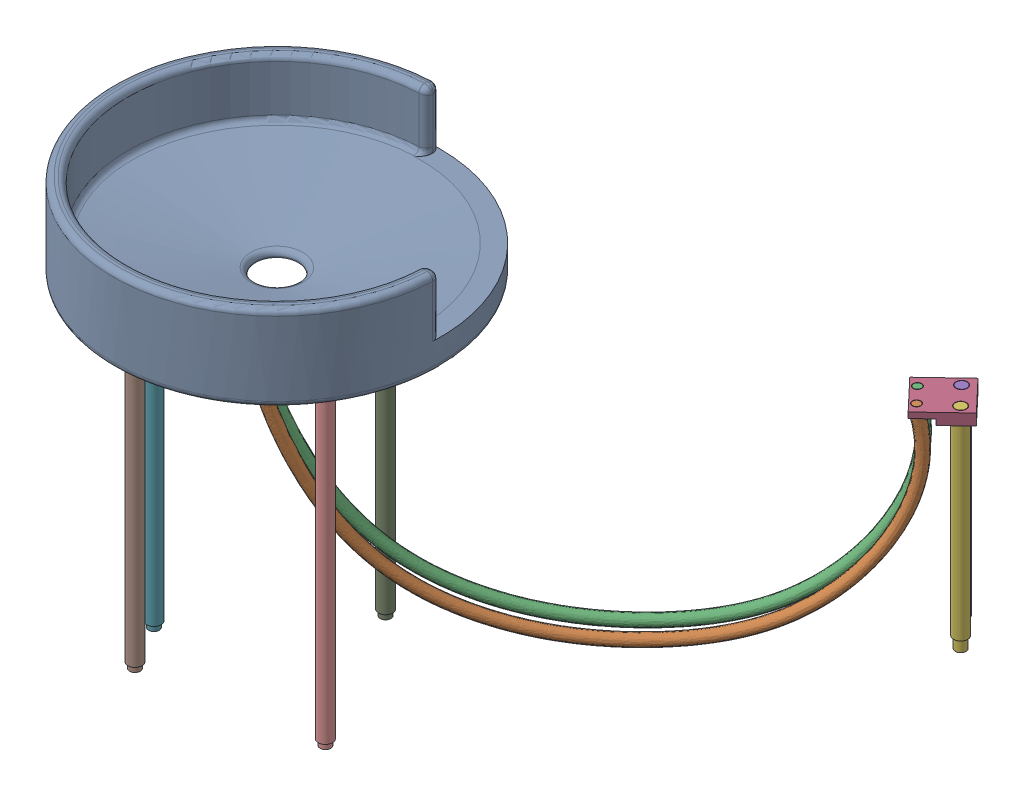
SolidWorks assembly Ensamblaje, configuration Predeterminado. Lengths in mm.
Overall size (176.61 150.24 195.69).
10 component instances, 5 part files, 20 mates.
Components (placement in the parent):
- Base-1: Base [Predeterminado] at (-10.0904 -19.4956 1.3876) size (115 30 115)
- Slide-1: Slide [Predeterminado] at (-13.6259 -19.4956 11.9942) x (0.642217 0 -0.766523) z (0 -1 0) size (175.9 4.02 118.54)
- Slide-2: Slide [Predeterminado] at (-20.697 -19.4956 4.9232) x (0.653468 0 -0.756954) z (0 -1 0) size (175.9 4.02 118.54)
- Little Base-1: Little Base [Predeterminado] at (96.6014 -65.7362 -124.4757) x (0.725915 0 -0.687784) z (-0.687784 0 -0.725915) size (17 4 15)
- Pilar Corto-1: Pilar Corto [Predeterminado] at (97.8618 -135.7362 -131.8691) x (0.841988 0 0.539497) z (-0.539497 0 0.841988) size (5 74 5)
- Pilar Corto-2: Pilar Corto [Predeterminado] at (104.0519 -135.7362 -125.3358) x (-0.528786 0 -0.848755) z (0.848755 0 -0.528786) size (5 74 5)
- Pilar Largo-1: Pilar Largo [Predeterminado] at (-44.241 -137.4956 10.5383) size (5 122 5)
- Pilar Largo-2: Pilar Largo [Predeterminado] at (-35.0904 -137.4956 26.3876) x (0.980301 0 0.197508) z (-0.197508 0 0.980301) size (5 122 5)
- Pilar Largo-3: Pilar Largo [Predeterminado] at (-7.009 -137.4956 -33.8332) size (5 122 5)
- Pilar Largo-4: Pilar Largo [Predeterminado] at (21.9524 -137.4956 16.3294) size (5 122 5)
Mates (geometry in assembly coordinates):
- Concéntrica2: concentric anti-aligned: circle of Base-1; circle of Slide-1
- Coincidente2: coincident anti-aligned: plane of Base-1 through (-13.6259 -17.4956 11.9942) normal (0 -1 0); plane of Slide-1 through (-13.6259 -17.4956 11.9942) normal (0 1 0)
- Concéntrica3: concentric anti-aligned: circle of Base-1; circle of Slide-2
- Coincidente3: coincident anti-aligned: plane of Base-1 through (-20.697 -17.4956 4.9232) normal (0 -1 0); plane of Slide-2 through (-20.697 -17.4956 4.9232) normal (0 1 0)
- Concéntrica4: concentric aligned: circle of Slide-1; circle of Little Base-1
- Concéntrica5: concentric aligned: circle of Slide-2; circle of Little Base-1
- Concéntrica12: concentric aligned: circle of Slide-2; circle of Little Base-1
- Concéntrica6: concentric anti-aligned: circle of Little Base-1; circle of Pilar Corto-1
- Coincidente5: coincident anti-aligned: plane of Little Base-1 through (96.6014 -69.7362 -124.4757) normal (0 -1 0); plane of Pilar Corto-1 through (97.8618 -69.7362 -131.8691) normal (0 1 0)
- Concéntrica7: concentric anti-aligned: circle of Little Base-1; circle of Pilar Corto-2
- Coincidente6: coincident anti-aligned: plane of Little Base-1 through (96.6014 -69.7362 -124.4757) normal (0 -1 0); plane of Pilar Corto-2 through (104.0519 -69.7362 -125.3358) normal (0 1 0)
- Concéntrica8: concentric anti-aligned: circle of Base-1; circle of Pilar Largo-2
- Coincidente7: coincident anti-aligned: plane of Base-1 through (-10.0904 -19.4956 56.8876) normal (0 -1 0); plane of Pilar Largo-2 through (-35.0904 -19.4956 26.3876) normal (0 1 0)
- Concéntrica9: concentric anti-aligned: circle of Base-1; circle of Pilar Largo-1
- Coincidente8: coincident anti-aligned: plane of Base-1 through (-10.0904 -19.4956 56.8876) normal (0 -1 0); plane of Pilar Largo-1 through (-44.241 -19.4956 10.5383) normal (0 1 0)
- Concéntrica10: concentric anti-aligned: circle of Base-1; circle of Pilar Largo-4
- Coincidente9: coincident anti-aligned: plane of Base-1 through (-10.0904 -19.4956 56.8876) normal (0 -1 0); plane of Pilar Largo-4 through (21.9524 -19.4956 16.3294) normal (0 1 0)
- Concéntrica11: concentric anti-aligned: circle of Base-1; circle of Pilar Largo-3
- Coincidente10: coincident anti-aligned: plane of Base-1 through (-10.0904 -19.4956 56.8876) normal (0 -1 0); plane of Pilar Largo-3 through (-7.009 -19.4956 -33.8332) normal (0 1 0)
- Coincidente11: coincident anti-aligned: plane of Slide-2 through (89.0979 -67.7362 -122.2593) normal (0 1 0); plane of Little Base-1 through (101.7598 -67.7362 -119.0314) normal (0 -1 0)
